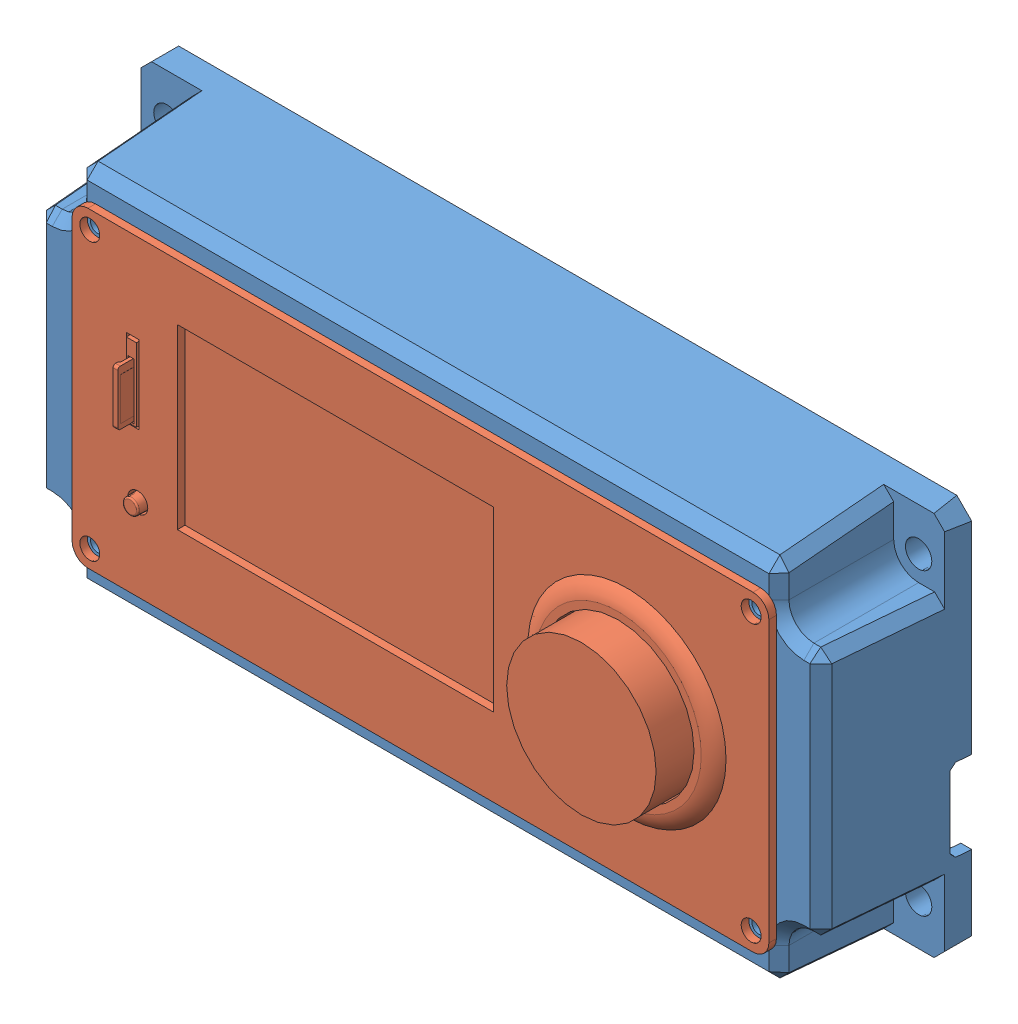
SolidWorks assembly Assem1, configuration Default. Lengths in mm.
Overall size (162 78 39.16).
2 component instances, 2 part files, 6 mates.
Components (placement in the parent):
- HercuLien_Viki2_Mount_Front_Face-1: HercuLien_Viki2_Mount_Front_Face [Default] x (-1 0 0) z (0 0 -1) size (162 78 28)
- Viki2_LCD-1: Viki2_LCD [Default] at (-21.825 26.0828 -7.239) x (1 0.00011 0) z (0 0 1) size (139.71 62.5 29.06)
Mates (geometry in assembly coordinates):
- Coincident1: coincident aligned: plane of HercuLien_Viki2_Mount_Front_Face-1 through (0 0 0) normal (0 0 1); plane of assembly
- Coincident2: coincident aligned: plane of HercuLien_Viki2_Mount_Front_Face-1; plane of assembly
- Coincident3: coincident anti-aligned: plane of HercuLien_Viki2_Mount_Front_Face-1 through (0 0 0) normal (-1 0 0); plane of assembly
- Coincident4: coincident: plane of HercuLien_Viki2_Mount_Front_Face-1 through (0 0 0) normal (0 0 1); plane of Viki2_LCD-1 through (16.5453 -95.3638 0) normal (0 0 -1)
- Concentric1: concentric: cylinder of HercuLien_Viki2_Mount_Front_Face-1 through (-66.3 27.7 -3) axis (0 0 1) radius 1.375; cylinder of Viki2_LCD-1 through (-66.3 27.7 1.524) axis (0 0 -1) radius 2
- Parallel2: parallel: line of HercuLien_Viki2_Mount_Front_Face-1 through (136.7 -68.35 -34.5503) axis (0 1 0); plane of Viki2_LCD-1 through (66.6703 -31.228 1.524) normal (0 -1 0)
